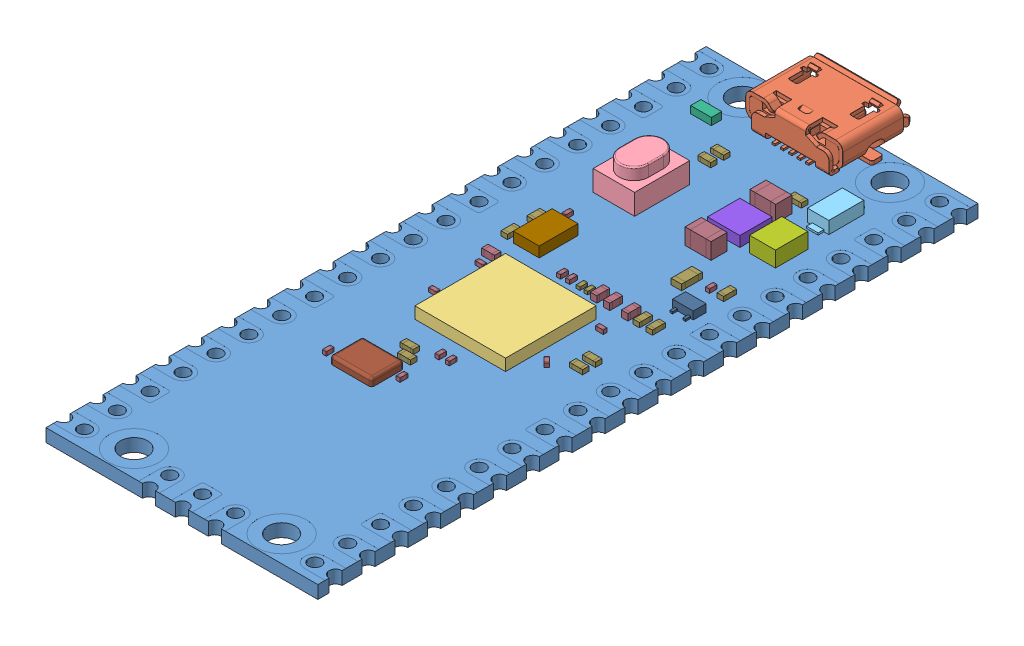
SolidWorks assembly Raspberry Pi Pico-R3, configuration Default. Lengths in mm.
Overall size (21 3.69 52.43).
44 component instances, 13 part files, 131 mates.
Components (placement in the parent):
- PCB, Raspberry Pi Pico-R3-1: PCB, Raspberry Pi Pico-R3 [Default] at origin size (21 1 51)
- MicroUSB Port, Raspberry Pi Pico-R3-1: MicroUSB Port, Raspberry Pi Pico-R3 [Default] at (0 0.5 -24.35) x (-1 0 0) z (0 0 -1) size (7.97 2.92 5.43)
- RP2040 Microcontroller, Raspberry Pi Pico-R3-1: RP2040 Microcontroller, Raspberry Pi Pico-R3 [Default] at (0 0.5 0.5) size (7 0.9 7)
- SW1, Tact Switch, Raspberry Pi Pico-R3-1: SW1, Tact Switch, Raspberry Pi Pico-R3 [Default] at (-3.5 0.5 -13.5) size (3.2 2.5 4.25)
- D1, Diode, Schottky, Raspberry Pi Pico-R3-1: D1, Diode, Schottky, Raspberry Pi Pico-R3 [Default] at (6 0.5 -19) size (1.65 0.95 3.6)
- D2, QSME-C194, LED, Raspberry Pi Pico-R3-1: D2, QSME-C194, LED, Raspberry Pi Pico-R3 [Default] at (-5.8 0.5 -20.8) size (1.6 0.55 0.8)
- L1, Inductor, Raspberry Pi Pico-R3-1: L1, Inductor, Raspberry Pi Pico-R3 [Default] at (6 0.5 -14.6) size (2 1.2 2.5)
- U2, RT6150B-33GQW, Buck Boost Converter, Raspberry Pi Pico-R3-1: U2, RT6150B-33GQW, Buck Boost Converter, Raspberry Pi Pico-R3 [Default] at (3 0.5 -14.6) size (2.5 0.8 2.5)
- U3, W25Q16JVUXIQ, Serial NOR Flash 16 Mbit, Raspberry Pi Pico-R3-1: U3, W25Q16JVUXIQ, Serial NOR Flash 16 Mbit, Raspberry Pi Pico-R3 [Default] at (-3.8 0.5 -6.4) size (2 0.8 3)
- Q1, MOSFET, DMG1012T, Raspberry Pi Pico-R3-1: Q1, MOSFET, DMG1012T, Raspberry Pi Pico-R3 [Default] at (6.5 0.5 -7.2) size (1.6 0.6 1.8)
- X1, X12M000000S096, 12 Mhz Crystal Resonator, Raspberry Pi Pico-R3-1: X1, X12M000000S096, 12 Mhz Crystal Resonator, Raspberry Pi Pico-R3 [Default] at (-2.2 0.5 9) size (3.2 0.6 2.5)
- SMD Resistor, Configurable, Raspberry Pi Pico-R3-1: SMD Resistor, Configurable, Raspberry Pi Pico-R3 [R1] at (6.2 0.5 1) x (0 0 -1) z (1 0 0) size (0.5 0.35 1)
- SMD Resistor, Configurable, Raspberry Pi Pico-R3-2: SMD Resistor, Configurable, Raspberry Pi Pico-R3 [R2] at (3.5 0.5 -18.6) x (0 0 -1) z (1 0 0) size (0.5 0.35 1)
- SMD Resistor, Configurable, Raspberry Pi Pico-R3-3: SMD Resistor, Configurable, Raspberry Pi Pico-R3 [R3] at (-2.7 0.5 -17.8) x (0 0 -1) z (1 0 0) size (0.5 0.35 1)
- SMD Resistor, Configurable, Raspberry Pi Pico-R3-4: SMD Resistor, Configurable, Raspberry Pi Pico-R3 [R4] at (-5.5 0.5 -5.4) x (-1 0 0) z (0 0 -1) size (0.5 0.35 1)
- SMD Resistor, Configurable, Raspberry Pi Pico-R3-5: SMD Resistor, Configurable, Raspberry Pi Pico-R3 [R5] at (7 0.5 -9.6) x (-1 0 0) z (0 0 -1) size (0.5 0.35 1)
- SMD Resistor, Configurable, Raspberry Pi Pico-R3-6: SMD Resistor, Configurable, Raspberry Pi Pico-R3 [R6] at (6.5 0.5 -4.6) x (-1 0 0) z (0 0 -1) size (0.5 0.35 1)
- SMD Resistor, Configurable, Raspberry Pi Pico-R3-7: SMD Resistor, Configurable, Raspberry Pi Pico-R3 [R7] at (4.5 0.5 -9) x (-1 0 0) z (0 0 -1) size (0.8 0.45 1.6)
- SMD Resistor, Configurable, Raspberry Pi Pico-R3-8: SMD Resistor, Configurable, Raspberry Pi Pico-R3 [R8] at (-2.7 0.5 -18.8) x (0 0 -1) z (1 0 0) size (0.5 0.35 1)
- SMD Resistor, Configurable, Raspberry Pi Pico-R3-9: SMD Resistor, Configurable, Raspberry Pi Pico-R3 [R9] at (5.5 0.5 -4.6) x (-1 0 0) z (0 0 -1) size (0.5 0.35 1)
- SMD Resistor, Configurable, Raspberry Pi Pico-R3-10: SMD Resistor, Configurable, Raspberry Pi Pico-R3 [R10] at (6.2 0.5 0) x (0 0 -1) z (1 0 0) size (0.5 0.35 1)
- SMD Resistor, Configurable, Raspberry Pi Pico-R3-11: SMD Resistor, Configurable, Raspberry Pi Pico-R3 [R11] at (-5.5 0.5 -7.4) size (0.5 0.35 1)
- SMD Resistor, Configurable, Raspberry Pi Pico-R3-12: SMD Resistor, Configurable, Raspberry Pi Pico-R3 [R12] at (0.8 0.5 -4.6) x (-1 0 0) z (0 0 -1) size (0.3 0.23 0.6)
- SMD Resistor, Configurable, Raspberry Pi Pico-R3-13: SMD Resistor, Configurable, Raspberry Pi Pico-R3 [R13] at (1.4 0.5 -4.6) x (-1 0 0) z (0 0 -1) size (0.3 0.23 0.6)
- SMD Resistor, Configurable, Raspberry Pi Pico-R3-14: SMD Resistor, Configurable, Raspberry Pi Pico-R3 [R14] at (-1.1 0.5 7) x (0 0 -1) z (1 0 0) size (0.5 0.35 1)
- SMD Resistor, Configurable, Raspberry Pi Pico-R3-15: SMD Resistor, Configurable, Raspberry Pi Pico-R3 [R15] at (-1.7 0.5 6.2) x (0 0 -1) z (1 0 0) size (0.5 0.35 1)
- SMD Capacitor, Configurable, Raspberry Pi Pico-R3-1: SMD Capacitor, Configurable, Raspberry Pi Pico-R3 [C1] at (3 0.5 -17) x (0 0 -1) z (1 0 0) size (1.25 1.25 2)
- SMD Capacitor, Configurable, Raspberry Pi Pico-R3-2: SMD Capacitor, Configurable, Raspberry Pi Pico-R3 [C2] at (3 0.5 -12) x (0 0 -1) z (1 0 0) size (1.25 1.25 2)
- SMD Capacitor, Configurable, Raspberry Pi Pico-R3-3: SMD Capacitor, Configurable, Raspberry Pi Pico-R3 [C3] at (6 0.5 -9.4) size (0.3 0.3 0.6)
- SMD Capacitor, Configurable, Raspberry Pi Pico-R3-4: SMD Capacitor, Configurable, Raspberry Pi Pico-R3 [C4] at (-4.5 0.5 -2.1) x (0 0 1) z (-1 0 0) size (0.3 0.3 0.6)
- SMD Capacitor, Configurable, Raspberry Pi Pico-R3-5: SMD Capacitor, Configurable, Raspberry Pi Pico-R3 [C5] at (-4.5 0.5 1.5) x (0 0 1) z (-1 0 0) size (0.3 0.3 0.6)
- SMD Capacitor, Configurable, Raspberry Pi Pico-R3-6: SMD Capacitor, Configurable, Raspberry Pi Pico-R3 [C6] at (4.6 0.5 1.9) x (0.707107 0 -0.707107) z (0.707107 0 0.707107) size (0.3 0.3 0.6)
- SMD Capacitor, Configurable, Raspberry Pi Pico-R3-7: SMD Capacitor, Configurable, Raspberry Pi Pico-R3 [C7] at (4.5 0.5 -2.4) x (0 0 1) z (-1 0 0) size (0.3 0.3 0.6)
- SMD Capacitor, Configurable, Raspberry Pi Pico-R3-8: SMD Capacitor, Configurable, Raspberry Pi Pico-R3 [C8] at (0 0.5 5.5) size (0.3 0.3 0.6)
- SMD Capacitor, Configurable, Raspberry Pi Pico-R3-9: SMD Capacitor, Configurable, Raspberry Pi Pico-R3 [C9] at (0.8 0.5 5.5) size (0.3 0.3 0.6)
- SMD Capacitor, Configurable, Raspberry Pi Pico-R3-10: SMD Capacitor, Configurable, Raspberry Pi Pico-R3 [C10] at (0 0.5 -4.6) size (0.3 0.3 0.6)
- SMD Capacitor, Configurable, Raspberry Pi Pico-R3-11: SMD Capacitor, Configurable, Raspberry Pi Pico-R3 [C11] at (-0.7 0.5 -4.6) size (0.3 0.3 0.6)
- SMD Capacitor, Configurable, Raspberry Pi Pico-R3-19: SMD Capacitor, Configurable, Raspberry Pi Pico-R3 [C12] at (2.2 0.5 -4.6) size (0.5 0.5 1)
- SMD Capacitor, Configurable, Raspberry Pi Pico-R3-20: SMD Capacitor, Configurable, Raspberry Pi Pico-R3 [C13] at (4.6 0.5 -4.6) size (0.5 0.5 1)
- SMD Capacitor, Configurable, Raspberry Pi Pico-R3-21: SMD Capacitor, Configurable, Raspberry Pi Pico-R3 [C14] at (3.2 0.5 -4.6) size (0.5 0.5 1)
- SMD Capacitor, Configurable, Raspberry Pi Pico-R3-22: SMD Capacitor, Configurable, Raspberry Pi Pico-R3 [C15] at (-4.5 0.5 -8.8) size (0.3 0.3 0.6)
- SMD Capacitor, Configurable, Raspberry Pi Pico-R3-23: SMD Capacitor, Configurable, Raspberry Pi Pico-R3 [C16] at (-4.6 0.5 9.6) size (0.3 0.3 0.6)
- SMD Capacitor, Configurable, Raspberry Pi Pico-R3-24: SMD Capacitor, Configurable, Raspberry Pi Pico-R3 [C17] at (0 0.5 8.5) size (0.3 0.3 0.6)
- SMD Capacitor, Configurable, Raspberry Pi Pico-R3-18: SMD Capacitor, Configurable, Raspberry Pi Pico-R3 [C18] at (-4.7 0.5 -3.1) x (0 0 1) z (-1 0 0) size (0.5 0.5 1)
Mates (geometry in assembly coordinates):
- Coincident1: coordinate: point of PCB, Raspberry Pi Pico-R3-1
- Coincident2: coincident anti-aligned: plane of MicroUSB Port, Raspberry Pi Pico-R3-1 through (0 0.5 -24.35) normal (-1 0 0)
- Coincident4: coincident aligned: plane of PCB, Raspberry Pi Pico-R3-1 through (0 0.5 0) normal (0 1 0); plane of MicroUSB Port, Raspberry Pi Pico-R3-1 through (0 0.5 -24.35) normal (0 1 0)
- Distance1: distance anti-aligned: plane of PCB, Raspberry Pi Pico-R3-1 through (-10.5 -0.5 -25.5) normal (0 0 -1); plane of MicroUSB Port, Raspberry Pi Pico-R3-1 through (-1.2 2.0268 -21.5) normal (0 0 1)
- Coincident5: coincident anti-aligned: plane of PCB, Raspberry Pi Pico-R3-1 through (0 0.5 0) normal (0 1 0); plane of RP2040 Microcontroller, Raspberry Pi Pico-R3-1 through (0 0.5 0.5) normal (0 -1 0)
- Coincident6: coincident aligned: plane of RP2040 Microcontroller, Raspberry Pi Pico-R3-1 through (0 0.5 0.5) normal (1 0 0)
- Coincident7: coincident anti-aligned: plane of PCB, Raspberry Pi Pico-R3-1 through (0 0.5 0) normal (0 1 0); plane of SW1, Tact Switch, Raspberry Pi Pico-R3-1 through (-3.5 0.5 -13.5) normal (0 -1 0)
- Distance2: distance = 3.5 mm aligned: plane of SW1, Tact Switch, Raspberry Pi Pico-R3-1 through (-3.5 0.5 -13.5) normal (1 0 0)
- Distance3: distance = 13.5 mm: plane of assembly through (0 0 0) normal (0 0 1); plane of assembly; plane of SW1, Tact Switch, Raspberry Pi Pico-R3-1 through (-3.5 0.5 -13.5) normal (0 0 1)
- Coincident8: coincident anti-aligned: plane of PCB, Raspberry Pi Pico-R3-1 through (0 0.5 0) normal (0 1 0); plane of D1, Diode, Schottky, Raspberry Pi Pico-R3-1 through (6 0.5 -19) normal (0 -1 0)
- Distance4: distance = 6 mm aligned: plane of D1, Diode, Schottky, Raspberry Pi Pico-R3-1 through (6 0.5 -19) normal (1 0 0)
- Distance5: distance = 19 mm: plane of assembly through (0 0 0) normal (0 0 1); plane of assembly; plane of D1, Diode, Schottky, Raspberry Pi Pico-R3-1 through (6 0.5 -19) normal (0 0 1)
- Coincident9: coincident anti-aligned: plane of PCB, Raspberry Pi Pico-R3-1 through (0 0.5 0) normal (0 1 0); plane of L1, Inductor, Raspberry Pi Pico-R3-1 through (6 0.5 -14.6) normal (0 -1 0)
- Coincident10: coincident aligned: plane of D1, Diode, Schottky, Raspberry Pi Pico-R3-1 through (6 0.5 -19) normal (1 0 0); plane of L1, Inductor, Raspberry Pi Pico-R3-1 through (6 0.5 -14.6) normal (1 0 0)
- Distance6: distance = 4.4 mm aligned: plane of L1, Inductor, Raspberry Pi Pico-R3-1 through (6 0.5 -14.6) normal (0 0 1); plane of D1, Diode, Schottky, Raspberry Pi Pico-R3-1 through (6 0.5 -19) normal (0 0 1)
- Coincident11: coincident anti-aligned: plane of PCB, Raspberry Pi Pico-R3-1 through (0 0.5 0) normal (0 1 0); plane of SMD Resistor, Configurable, Raspberry Pi Pico-R3-1 through (6.2 0.5 1) normal (0 -1 0)
- Distance8: distance = 6.2 mm aligned: plane of SMD Resistor, Configurable, Raspberry Pi Pico-R3-1 through (6.2 0.5 1) normal (1 0 0)
- Distance9: distance = 1 mm anti-aligned: plane of SMD Resistor, Configurable, Raspberry Pi Pico-R3-1 through (6.2 0.5 1) normal (0 0 -1)
- Coincident13: coincident anti-aligned: plane of PCB, Raspberry Pi Pico-R3-1 through (0 0.5 0) normal (0 1 0); plane of SMD Resistor, Configurable, Raspberry Pi Pico-R3-2 through (3.5 0.5 -18.6) normal (0 -1 0)
- Distance10: distance = 3.5 mm aligned: plane of SMD Resistor, Configurable, Raspberry Pi Pico-R3-2 through (3.5 0.5 -18.6) normal (1 0 0)
- Distance11: distance = 18.6 mm anti-aligned: plane of SMD Resistor, Configurable, Raspberry Pi Pico-R3-2 through (3.5 0.5 -18.6) normal (0 0 -1)
- Coincident14: coincident anti-aligned: plane of PCB, Raspberry Pi Pico-R3-1 through (0 0.5 0) normal (0 1 0); plane of SMD Resistor, Configurable, Raspberry Pi Pico-R3-3 through (-2.7 0.5 -17.8) normal (0 -1 0)
- Coincident15: coincident anti-aligned: plane of PCB, Raspberry Pi Pico-R3-1 through (0 0.5 0) normal (0 1 0); plane of SMD Resistor, Configurable, Raspberry Pi Pico-R3-4 through (-5.5 0.5 -5.4) normal (0 -1 0)
- Coincident16: coincident anti-aligned: plane of PCB, Raspberry Pi Pico-R3-1 through (0 0.5 0) normal (0 1 0); plane of SMD Resistor, Configurable, Raspberry Pi Pico-R3-5 through (7 0.5 -9.6) normal (0 -1 0)
- Coincident17: coincident anti-aligned: plane of PCB, Raspberry Pi Pico-R3-1 through (0 0.5 0) normal (0 1 0); plane of SMD Resistor, Configurable, Raspberry Pi Pico-R3-6 through (6.5 0.5 -4.6) normal (0 -1 0)
- Coincident18: coincident anti-aligned: plane of PCB, Raspberry Pi Pico-R3-1 through (0 0.5 0) normal (0 1 0); plane of SMD Resistor, Configurable, Raspberry Pi Pico-R3-7 through (4.5 0.5 -9) normal (0 -1 0)
- Coincident19: coincident anti-aligned: plane of PCB, Raspberry Pi Pico-R3-1 through (0 0.5 0) normal (0 1 0); plane of SMD Resistor, Configurable, Raspberry Pi Pico-R3-8 through (-2.7 0.5 -18.8) normal (0 -1 0)
- Coincident20: coincident anti-aligned: plane of PCB, Raspberry Pi Pico-R3-1 through (0 0.5 0) normal (0 1 0); plane of SMD Resistor, Configurable, Raspberry Pi Pico-R3-9 through (5.5 0.5 -4.6) normal (0 -1 0)
- Coincident21: coincident anti-aligned: plane of PCB, Raspberry Pi Pico-R3-1 through (0 0.5 0) normal (0 1 0); plane of SMD Resistor, Configurable, Raspberry Pi Pico-R3-10 through (6.2 0.5 0) normal (0 -1 0)
- Coincident22: coincident anti-aligned: plane of PCB, Raspberry Pi Pico-R3-1 through (0 0.5 0) normal (0 1 0); plane of SMD Resistor, Configurable, Raspberry Pi Pico-R3-11 through (-5.5 0.5 -7.4) normal (0 -1 0)
- Coincident23: coincident anti-aligned: plane of PCB, Raspberry Pi Pico-R3-1 through (0 0.5 0) normal (0 1 0); plane of SMD Resistor, Configurable, Raspberry Pi Pico-R3-12 through (0.8 0.5 -4.6) normal (0 -1 0)
- Coincident24: coincident anti-aligned: plane of PCB, Raspberry Pi Pico-R3-1 through (0 0.5 0) normal (0 1 0); plane of SMD Resistor, Configurable, Raspberry Pi Pico-R3-13 through (1.4 0.5 -4.6) normal (0 -1 0)
- Coincident25: coincident anti-aligned: plane of PCB, Raspberry Pi Pico-R3-1 through (0 0.5 0) normal (0 1 0); plane of SMD Resistor, Configurable, Raspberry Pi Pico-R3-14 through (-1.1 0.5 7) normal (0 -1 0)
- Coincident26: coincident anti-aligned: plane of PCB, Raspberry Pi Pico-R3-1 through (0 0.5 0) normal (0 1 0); plane of SMD Resistor, Configurable, Raspberry Pi Pico-R3-15 through (-1.7 0.5 6.2) normal (0 -1 0)
- Distance12: distance = 2.7 mm aligned: plane of SMD Resistor, Configurable, Raspberry Pi Pico-R3-3 through (-2.7 0.5 -17.8) normal (1 0 0)
- Coincident27: coincident aligned: plane of SMD Resistor, Configurable, Raspberry Pi Pico-R3-3 through (-2.7 0.5 -17.8) normal (1 0 0); plane of SMD Resistor, Configurable, Raspberry Pi Pico-R3-8 through (-2.7 0.5 -18.8) normal (1 0 0)
- Distance14: distance = 1 mm aligned: plane of SMD Resistor, Configurable, Raspberry Pi Pico-R3-3 through (-2.7 0.5 -17.8) normal (0 0 -1); plane of SMD Resistor, Configurable, Raspberry Pi Pico-R3-8 through (-2.7 0.5 -18.8) normal (0 0 -1)
- Distance15: distance = 17.8 mm anti-aligned: plane of SMD Resistor, Configurable, Raspberry Pi Pico-R3-3 through (-2.7 0.5 -17.8) normal (0 0 -1)
- Coincident28: coincident anti-aligned: plane of SMD Resistor, Configurable, Raspberry Pi Pico-R3-4 through (-5.5 0.5 -5.4) normal (-1 0 0); plane of SMD Resistor, Configurable, Raspberry Pi Pico-R3-11 through (-5.5 0.5 -7.4) normal (1 0 0)
- Distance16: distance = 5.5 mm: plane of assembly through (0 0 0) normal (1 0 0); plane of assembly; plane of SMD Resistor, Configurable, Raspberry Pi Pico-R3-4 through (-5.5 0.5 -5.4) normal (-1 0 0)
- Distance17: distance = 5.4 mm anti-aligned: plane of SMD Resistor, Configurable, Raspberry Pi Pico-R3-4 through (-5.5 0.5 -5.4) normal (0 0 -1)
- Distance18: distance = 2 mm anti-aligned: plane of SMD Resistor, Configurable, Raspberry Pi Pico-R3-4 through (-5.5 0.5 -5.4) normal (0 0 -1); plane of SMD Resistor, Configurable, Raspberry Pi Pico-R3-11 through (-5.5 0.5 -7.4) normal (0 0 1)
- Distance19: distance = 4.5 mm anti-aligned: plane of SMD Resistor, Configurable, Raspberry Pi Pico-R3-7 through (4.5 0.5 -9) normal (-1 0 0)
- Distance20: distance = 9 mm anti-aligned: plane of SMD Resistor, Configurable, Raspberry Pi Pico-R3-7 through (4.5 0.5 -9) normal (0 0 -1)
- Distance21: distance = 7 mm anti-aligned: plane of SMD Resistor, Configurable, Raspberry Pi Pico-R3-5 through (7 0.5 -9.6) normal (-1 0 0)
- Distance22: distance = 9.6 mm anti-aligned: plane of SMD Resistor, Configurable, Raspberry Pi Pico-R3-5 through (7 0.5 -9.6) normal (0 0 -1)
- Coincident29: coincident aligned: plane of SMD Resistor, Configurable, Raspberry Pi Pico-R3-6 through (6.5 0.5 -4.6) normal (0 0 -1); plane of SMD Resistor, Configurable, Raspberry Pi Pico-R3-9 through (5.5 0.5 -4.6) normal (0 0 -1)
- Distance23: distance = 6.5 mm anti-aligned: plane of SMD Resistor, Configurable, Raspberry Pi Pico-R3-6 through (6.5 0.5 -4.6) normal (-1 0 0)
- Distance24: distance = 1 mm aligned: plane of SMD Resistor, Configurable, Raspberry Pi Pico-R3-9 through (5.5 0.5 -4.6) normal (-1 0 0); plane of SMD Resistor, Configurable, Raspberry Pi Pico-R3-6 through (6.5 0.5 -4.6) normal (-1 0 0)
- Coincident30: coincident aligned: plane of SMD Resistor, Configurable, Raspberry Pi Pico-R3-1 through (6.2 0.5 1) normal (1 0 0); plane of SMD Resistor, Configurable, Raspberry Pi Pico-R3-10 through (6.2 0.5 0) normal (1 0 0)
- Distance25: distance = 1 mm aligned: plane of SMD Resistor, Configurable, Raspberry Pi Pico-R3-1 through (6.2 0.5 1) normal (0 0 -1); plane of SMD Resistor, Configurable, Raspberry Pi Pico-R3-10 through (6.2 0.5 0) normal (0 0 -1)
- Distance26: distance = 0.8 mm anti-aligned: plane of SMD Resistor, Configurable, Raspberry Pi Pico-R3-12 through (0.8 0.5 -4.6) normal (-1 0 0)
- Distance27: distance = 0.6 mm aligned: plane of SMD Resistor, Configurable, Raspberry Pi Pico-R3-13 through (1.4 0.5 -4.6) normal (-1 0 0); plane of SMD Resistor, Configurable, Raspberry Pi Pico-R3-12 through (0.8 0.5 -4.6) normal (-1 0 0)
- Coincident31: coincident aligned: plane of SMD Resistor, Configurable, Raspberry Pi Pico-R3-12 through (0.8 0.5 -4.6) normal (0 0 -1); plane of SMD Resistor, Configurable, Raspberry Pi Pico-R3-13 through (1.4 0.5 -4.6) normal (0 0 -1)
- Distance28: distance = 4.6 mm anti-aligned: plane of SMD Resistor, Configurable, Raspberry Pi Pico-R3-12 through (0.8 0.5 -4.6) normal (0 0 -1)
- Distance29: distance = 0.6 mm aligned: plane of SMD Resistor, Configurable, Raspberry Pi Pico-R3-14 through (-1.1 0.5 7) normal (1 0 0); plane of SMD Resistor, Configurable, Raspberry Pi Pico-R3-15 through (-1.7 0.5 6.2) normal (1 0 0)
- Distance30: distance = 0.8 mm aligned: plane of SMD Resistor, Configurable, Raspberry Pi Pico-R3-14 through (-1.1 0.5 7) normal (0 0 -1); plane of SMD Resistor, Configurable, Raspberry Pi Pico-R3-15 through (-1.7 0.5 6.2) normal (0 0 -1)
- Distance31: distance = 7 mm anti-aligned: plane of SMD Resistor, Configurable, Raspberry Pi Pico-R3-14 through (-1.1 0.5 7) normal (0 0 -1)
- Distance32: distance = 4.6 mm anti-aligned: plane of SMD Resistor, Configurable, Raspberry Pi Pico-R3-9 through (5.5 0.5 -4.6) normal (0 0 -1)
- Distance33: distance = 0.5 mm aligned: plane of RP2040 Microcontroller, Raspberry Pi Pico-R3-1 through (0 0.5 0.5) normal (0 0 1)
- Distance34: distance = 1.1 mm aligned: plane of SMD Resistor, Configurable, Raspberry Pi Pico-R3-14 through (-1.1 0.5 7) normal (1 0 0)
- Coincident32: coincident anti-aligned: plane of PCB, Raspberry Pi Pico-R3-1 through (0 0.5 0) normal (0 1 0); plane of SMD Capacitor, Configurable, Raspberry Pi Pico-R3-1 through (3 0.5 -17) normal (0 -1 0)
- Coincident33: coincident anti-aligned: plane of PCB, Raspberry Pi Pico-R3-1 through (0 0.5 0) normal (0 1 0); plane of SMD Capacitor, Configurable, Raspberry Pi Pico-R3-2 through (3 0.5 -12) normal (0 -1 0)
- Coincident34: coincident anti-aligned: plane of PCB, Raspberry Pi Pico-R3-1 through (0 0.5 0) normal (0 1 0); plane of SMD Capacitor, Configurable, Raspberry Pi Pico-R3-3 through (6 0.5 -9.4) normal (0 -1 0)
- Coincident35: coincident anti-aligned: plane of PCB, Raspberry Pi Pico-R3-1 through (0 0.5 0) normal (0 1 0); plane of SMD Capacitor, Configurable, Raspberry Pi Pico-R3-18 through (-4.7 0.5 -3.1) normal (0 -1 0)
- Coincident36: coincident anti-aligned: plane of PCB, Raspberry Pi Pico-R3-1 through (0 0.5 0) normal (0 1 0); plane of SMD Capacitor, Configurable, Raspberry Pi Pico-R3-10 through (0 0.5 -4.6) normal (0 -1 0)
- Coincident37: coincident anti-aligned: plane of PCB, Raspberry Pi Pico-R3-1 through (0 0.5 0) normal (0 1 0); plane of SMD Capacitor, Configurable, Raspberry Pi Pico-R3-9 through (0.8 0.5 5.5) normal (0 -1 0)
- Coincident38: coincident anti-aligned: plane of PCB, Raspberry Pi Pico-R3-1 through (0 0.5 0) normal (0 1 0); plane of SMD Capacitor, Configurable, Raspberry Pi Pico-R3-8 through (0 0.5 5.5) normal (0 -1 0)
- Coincident39: coincident anti-aligned: plane of PCB, Raspberry Pi Pico-R3-1 through (0 0.5 0) normal (0 1 0); plane of SMD Capacitor, Configurable, Raspberry Pi Pico-R3-7 through (4.5 0.5 -2.4) normal (0 -1 0)
- Coincident40: coincident anti-aligned: plane of PCB, Raspberry Pi Pico-R3-1 through (0 0.5 0) normal (0 1 0); plane of SMD Capacitor, Configurable, Raspberry Pi Pico-R3-6 through (4.6 0.5 1.9) normal (0 -1 0)
- Coincident41: coincident anti-aligned: plane of PCB, Raspberry Pi Pico-R3-1 through (0 0.5 0) normal (0 1 0); plane of SMD Capacitor, Configurable, Raspberry Pi Pico-R3-5 through (-4.5 0.5 1.5) normal (0 -1 0)
- Coincident42: coincident anti-aligned: plane of PCB, Raspberry Pi Pico-R3-1 through (0 0.5 0) normal (0 1 0); plane of SMD Capacitor, Configurable, Raspberry Pi Pico-R3-4 through (-4.5 0.5 -2.1) normal (0 -1 0)
- Coincident43: coincident anti-aligned: plane of PCB, Raspberry Pi Pico-R3-1 through (0 0.5 0) normal (0 1 0); plane of SMD Capacitor, Configurable, Raspberry Pi Pico-R3-11 through (-0.7 0.5 -4.6) normal (0 -1 0)
- Coincident44: coincident anti-aligned: plane of PCB, Raspberry Pi Pico-R3-1 through (0 0.5 0) normal (0 1 0); plane of SMD Capacitor, Configurable, Raspberry Pi Pico-R3-19 through (2.2 0.5 -4.6) normal (0 -1 0)
- Coincident45: coincident anti-aligned: plane of PCB, Raspberry Pi Pico-R3-1 through (0 0.5 0) normal (0 1 0); plane of SMD Capacitor, Configurable, Raspberry Pi Pico-R3-20 through (4.6 0.5 -4.6) normal (0 -1 0)
- Coincident46: coincident anti-aligned: plane of PCB, Raspberry Pi Pico-R3-1 through (0 0.5 0) normal (0 1 0); plane of SMD Capacitor, Configurable, Raspberry Pi Pico-R3-21 through (3.2 0.5 -4.6) normal (0 -1 0)
- Coincident47: coincident anti-aligned: plane of PCB, Raspberry Pi Pico-R3-1 through (0 0.5 0) normal (0 1 0); plane of SMD Capacitor, Configurable, Raspberry Pi Pico-R3-22 through (-4.5 0.5 -8.8) normal (0 -1 0)
- Coincident48: coincident anti-aligned: plane of PCB, Raspberry Pi Pico-R3-1 through (0 0.5 0) normal (0 1 0); plane of SMD Capacitor, Configurable, Raspberry Pi Pico-R3-23 through (-4.6 0.5 9.6) normal (0 -1 0)
- Coincident49: coincident anti-aligned: plane of PCB, Raspberry Pi Pico-R3-1 through (0 0.5 0) normal (0 1 0); plane of SMD Capacitor, Configurable, Raspberry Pi Pico-R3-24 through (0 0.5 8.5) normal (0 -1 0)
- Coincident50: coincident aligned: plane of SMD Capacitor, Configurable, Raspberry Pi Pico-R3-1 through (3 0.5 -17) normal (1 0 0); plane of SMD Capacitor, Configurable, Raspberry Pi Pico-R3-2 through (3 0.5 -12) normal (1 0 0)
- Distance35: distance = 3 mm aligned: plane of SMD Capacitor, Configurable, Raspberry Pi Pico-R3-1 through (3 0.5 -17) normal (1 0 0)
- Distance36: distance = 17 mm anti-aligned: plane of SMD Capacitor, Configurable, Raspberry Pi Pico-R3-1 through (3 0.5 -17) normal (0 0 -1)
- Distance37: distance = 12 mm anti-aligned: plane of SMD Capacitor, Configurable, Raspberry Pi Pico-R3-2 through (3 0.5 -12) normal (0 0 -1)
- Distance38: distance = 4.5 mm aligned: plane of SMD Capacitor, Configurable, Raspberry Pi Pico-R3-22 through (-4.5 0.5 -8.8) normal (1 0 0)
- Distance39: distance = 8.8 mm aligned: plane of SMD Capacitor, Configurable, Raspberry Pi Pico-R3-22 through (-4.5 0.5 -8.8) normal (0 0 1)
- Distance40: distance = 4.6 mm aligned: plane of SMD Capacitor, Configurable, Raspberry Pi Pico-R3-23 through (-4.6 0.5 9.6) normal (1 0 0)
- Distance41: distance = 9.6 mm aligned: plane of SMD Capacitor, Configurable, Raspberry Pi Pico-R3-23 through (-4.6 0.5 9.6) normal (0 0 1)
- Distance42: distance = 0 mm aligned: plane of SMD Capacitor, Configurable, Raspberry Pi Pico-R3-24 through (0 0.5 8.5) normal (1 0 0)
- Distance43: distance = 8.5 mm aligned: plane of SMD Capacitor, Configurable, Raspberry Pi Pico-R3-24 through (0 0.5 8.5) normal (0 0 1)
- Distance44: distance = 1.5 mm aligned: plane of SMD Capacitor, Configurable, Raspberry Pi Pico-R3-5 through (-4.5 0.5 1.5) normal (0 0 1)
- Distance45: distance = 4.5 mm anti-aligned: plane of SMD Capacitor, Configurable, Raspberry Pi Pico-R3-5 through (-4.5 0.5 1.5) normal (-1 0 0)
- Coincident54: coincident aligned: plane of SMD Capacitor, Configurable, Raspberry Pi Pico-R3-4 through (-4.5 0.5 -2.1) normal (-1 0 0); plane of SMD Capacitor, Configurable, Raspberry Pi Pico-R3-5 through (-4.5 0.5 1.5) normal (-1 0 0)
- Distance46: distance = 3.6 mm aligned: plane of SMD Capacitor, Configurable, Raspberry Pi Pico-R3-4 through (-4.5 0.5 -2.1) normal (0 0 1); plane of SMD Capacitor, Configurable, Raspberry Pi Pico-R3-5 through (-4.5 0.5 1.5) normal (0 0 1)
- Coincident55: coincident aligned: plane of SMD Capacitor, Configurable, Raspberry Pi Pico-R3-8 through (0 0.5 5.5) normal (0 0 1); plane of SMD Capacitor, Configurable, Raspberry Pi Pico-R3-9 through (0.8 0.5 5.5) normal (0 0 1)
- Coincident56: coincident aligned: plane of SMD Capacitor, Configurable, Raspberry Pi Pico-R3-8 through (0 0.5 5.5) normal (1 0 0)
- Distance47: distance = 0.8 mm aligned: plane of SMD Capacitor, Configurable, Raspberry Pi Pico-R3-9 through (0.8 0.5 5.5) normal (1 0 0); plane of SMD Capacitor, Configurable, Raspberry Pi Pico-R3-8 through (0 0.5 5.5) normal (1 0 0)
- Distance48: distance = 5.5 mm aligned: plane of SMD Capacitor, Configurable, Raspberry Pi Pico-R3-8 through (0 0.5 5.5) normal (0 0 1)
- Distance49: distance = 4.7 mm anti-aligned: plane of SMD Capacitor, Configurable, Raspberry Pi Pico-R3-18 through (-4.7 0.5 -3.1) normal (-1 0 0)
- Distance50: distance = 1 mm aligned: plane of SMD Capacitor, Configurable, Raspberry Pi Pico-R3-18 through (-4.7 0.5 -3.1) normal (0 0 1); plane of SMD Capacitor, Configurable, Raspberry Pi Pico-R3-4 through (-4.5 0.5 -2.1) normal (0 0 1)
- Distance51: distance = 4.5 mm anti-aligned: plane of SMD Capacitor, Configurable, Raspberry Pi Pico-R3-7 through (4.5 0.5 -2.4) normal (-1 0 0)
- Distance52: distance = 2.4 mm aligned: plane of SMD Capacitor, Configurable, Raspberry Pi Pico-R3-7 through (4.5 0.5 -2.4) normal (0 0 1)
- Angle1: planar angle = 0.785398 rad aligned: plane of SMD Capacitor, Configurable, Raspberry Pi Pico-R3-6 through (4.6 0.5 1.9) normal (0.707107 0 -0.707107)
- Distance53: distance = 4.6 mm: unknown of SMD Capacitor, Configurable, Raspberry Pi Pico-R3-6
- Distance54: distance = 1.9 mm: unknown of SMD Capacitor, Configurable, Raspberry Pi Pico-R3-6
- Coincident61: coincident anti-aligned: plane of SMD Resistor, Configurable, Raspberry Pi Pico-R3-9 through (5.5 0.5 -4.6) normal (0 0 -1); plane of SMD Capacitor, Configurable, Raspberry Pi Pico-R3-20 through (4.6 0.5 -4.6) normal (0 0 1)
- Coincident62: coincident aligned: plane of SMD Capacitor, Configurable, Raspberry Pi Pico-R3-20 through (4.6 0.5 -4.6) normal (0 0 1); plane of SMD Capacitor, Configurable, Raspberry Pi Pico-R3-10 through (0 0.5 -4.6) normal (0 0 1)
- Coincident63: coincident aligned: plane of SMD Capacitor, Configurable, Raspberry Pi Pico-R3-20 through (4.6 0.5 -4.6) normal (0 0 1); plane of SMD Capacitor, Configurable, Raspberry Pi Pico-R3-11 through (-0.7 0.5 -4.6) normal (0 0 1)
- Coincident64: coincident aligned: plane of SMD Capacitor, Configurable, Raspberry Pi Pico-R3-20 through (4.6 0.5 -4.6) normal (0 0 1); plane of SMD Capacitor, Configurable, Raspberry Pi Pico-R3-19 through (2.2 0.5 -4.6) normal (0 0 1)
- Coincident65: coincident aligned: plane of SMD Capacitor, Configurable, Raspberry Pi Pico-R3-20 through (4.6 0.5 -4.6) normal (0 0 1); plane of SMD Capacitor, Configurable, Raspberry Pi Pico-R3-21 through (3.2 0.5 -4.6) normal (0 0 1)
- Distance55: distance = 4.6 mm aligned: plane of SMD Capacitor, Configurable, Raspberry Pi Pico-R3-20 through (4.6 0.5 -4.6) normal (1 0 0)
- Distance56: distance = 3.2 mm aligned: plane of SMD Capacitor, Configurable, Raspberry Pi Pico-R3-21 through (3.2 0.5 -4.6) normal (1 0 0)
- Distance57: distance = 2.2 mm aligned: plane of SMD Capacitor, Configurable, Raspberry Pi Pico-R3-19 through (2.2 0.5 -4.6) normal (1 0 0)
- Coincident66: coincident aligned: plane of SMD Capacitor, Configurable, Raspberry Pi Pico-R3-10 through (0 0.5 -4.6) normal (1 0 0)
- Distance58: distance = 0.7 mm aligned: plane of SMD Capacitor, Configurable, Raspberry Pi Pico-R3-11 through (-0.7 0.5 -4.6) normal (1 0 0)
- Distance59: distance = 6 mm aligned: plane of SMD Capacitor, Configurable, Raspberry Pi Pico-R3-3 through (6 0.5 -9.4) normal (1 0 0)
- Distance60: distance = 9.4 mm aligned: plane of SMD Capacitor, Configurable, Raspberry Pi Pico-R3-3 through (6 0.5 -9.4) normal (0 0 1)
- Coincident67: coincident anti-aligned: plane of PCB, Raspberry Pi Pico-R3-1 through (0 0.5 0) normal (0 1 0); plane of U2, RT6150B-33GQW, Buck Boost Converter, Raspberry Pi Pico-R3-1 through (3 0.5 -14.6) normal (0 -1 0)
- Coincident68: coincident aligned: plane of SMD Capacitor, Configurable, Raspberry Pi Pico-R3-1 through (3 0.5 -17) normal (1 0 0); plane of U2, RT6150B-33GQW, Buck Boost Converter, Raspberry Pi Pico-R3-1 through (3 0.5 -14.6) normal (1 0 0)
- Distance61: distance = 14.6 mm aligned: plane of U2, RT6150B-33GQW, Buck Boost Converter, Raspberry Pi Pico-R3-1 through (3 0.5 -14.6) normal (0 0 1)
- Coincident69: coincident anti-aligned: plane of PCB, Raspberry Pi Pico-R3-1 through (0 0.5 0) normal (0 1 0); plane of U3, W25Q16JVUXIQ, Serial NOR Flash 16 Mbit, Raspberry Pi Pico-R3-1 through (-3.8 0.5 -6.4) normal (0 -1 0)
- Distance62: distance = 3.8 mm aligned: plane of U3, W25Q16JVUXIQ, Serial NOR Flash 16 Mbit, Raspberry Pi Pico-R3-1 through (-3.8 0.5 -6.4) normal (1 0 0)
- Distance63: distance = 6.4 mm aligned: plane of U3, W25Q16JVUXIQ, Serial NOR Flash 16 Mbit, Raspberry Pi Pico-R3-1 through (-3.8 0.5 -6.4) normal (0 0 1)
- Coincident70: coincident anti-aligned: plane of PCB, Raspberry Pi Pico-R3-1 through (0 0.5 0) normal (0 1 0); plane of D2, QSME-C194, LED, Raspberry Pi Pico-R3-1 through (-5.8 0.5 -20.8) normal (0 -1 0)
- Distance64: distance = 5.8 mm aligned: plane of D2, QSME-C194, LED, Raspberry Pi Pico-R3-1 through (-5.8 0.5 -20.8) normal (1 0 0)
- Distance65: distance = 20.8 mm aligned: plane of D2, QSME-C194, LED, Raspberry Pi Pico-R3-1 through (-5.8 0.5 -20.8) normal (0 0 1)
- Coincident71: coincident anti-aligned: plane of PCB, Raspberry Pi Pico-R3-1 through (0 0.5 0) normal (0 1 0); plane of Q1, MOSFET, DMG1012T, Raspberry Pi Pico-R3-1 through (6.5 0.5 -7.2) normal (0 -1 0)
- Distance66: distance = 6.5 mm aligned: plane of Q1, MOSFET, DMG1012T, Raspberry Pi Pico-R3-1 through (6.5 0.5 -7.2) normal (1 0 0)
- Distance67: distance = 7.2 mm aligned: plane of Q1, MOSFET, DMG1012T, Raspberry Pi Pico-R3-1 through (6.5 0.5 -7.2) normal (0 0 1)
- Distance691: distance = 2.2 mm aligned: plane of X1, X12M000000S096, 12 Mhz Crystal Resonator, Raspberry Pi Pico-R3-1 through (-2.2 0.5 9) normal (1 0 0)
- Distance701: distance = 9 mm aligned: plane of X1, X12M000000S096, 12 Mhz Crystal Resonator, Raspberry Pi Pico-R3-1 through (-2.2 0.5 9) normal (0 0 1)
- Coincident72: coincident anti-aligned: plane of PCB, Raspberry Pi Pico-R3-1 through (0 0.5 0) normal (0 1 0); plane of X1, X12M000000S096, 12 Mhz Crystal Resonator, Raspberry Pi Pico-R3-1 through (-2.2 0.5 9) normal (0 -1 0)
